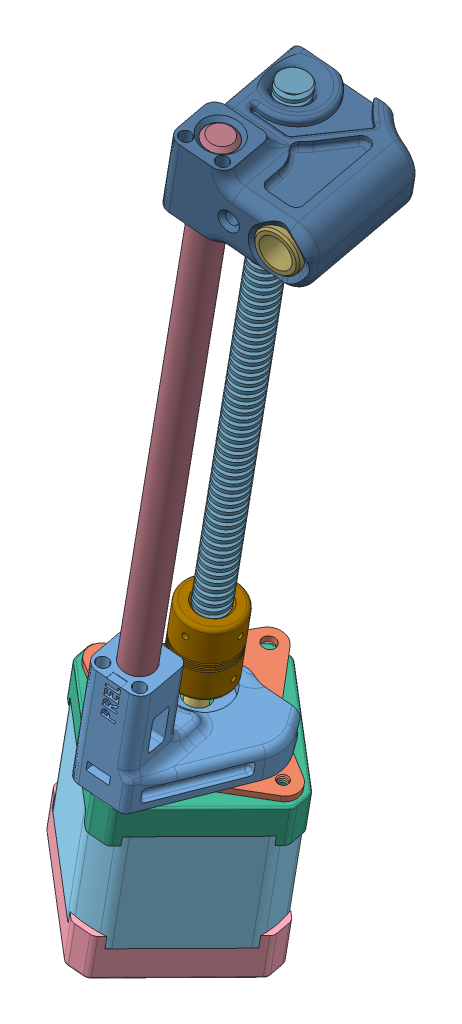
SolidWorks assembly PRUSA 3i elevator, configuration Default. Lengths in mm.
Overall size (115.58 237.83 82.21).
21 component instances, 14 part files, 7 mates.
Components (placement in the parent):
- lead motor assy-1: lead motor assy [Default] at (-145.707 134.5483 194.624) x (-0.101437 0.10188 -0.989612) z (0.968806 -0.21597 -0.121539) size (60.3 83.9 59.73)
  - x motor lead-1: x motor lead [Default] at (1.0016 21.1815 58.4436) size (38.44 32 28.56)
  - Nema 17 Damper v2-1: Nema 17 Damper v2 [Default] at (1.0013 -26.8185 65.4439) x (0.000014 0 -1) z (-1 0 -0.000014) size (52.04 7.74 51.84)
  - 17HM19-2004S-1: 17HM19-2004S [Default] at (-7.0367 -101.7185 75.8822) x (0.703083 0 -0.711108) z (0.711108 0 0.703083) size (42.24 72 42.24)
    - nema17_shaft_17HM19-2004S-1: nema17_shaft_17HM19-2004S [Default] at (13.0746 21 -1.623) x (-0.412738 0 0.91085) z (-0.91085 0 -0.412738) size (5 72 5)
    - nema17_bottom_17HM19-2004S-1: nema17_bottom_17HM19-2004S [Default] at (13.0746 21 -1.623) x (0.999984 0 0.005702) z (-0.005702 0 0.999984) size (42 12 42)
    - nema17_middle_17HM19-2004S-1: nema17_middle_17HM19-2004S [Default] at (13.0746 29.5 -1.623) x (0.999984 0 0.005702) z (-0.005702 0 0.999984) size (42 31.5 42)
    - nema17_top_17HM19-2004S-1: nema17_top_17HM19-2004S [Default] at (13.0746 61 -1.623) x (0.999984 0 0.005702) z (-0.005702 0 0.999984) size (42 12.6 42)
    - radial ball bearing_68_din_DIN 625 - 625 - 8,SI,NC,8_68-1: radial ball bearing_68_din_DIN 625 - 625 - 8,SI,NC,8_68 [Default] at (13.0746 26 -1.623) x (0 -1 0) z (0 0 1) size (5.01 16 16)
    - radial ball bearing_68_din_DIN 625 - 625 - 8,SI,NC,8_68-2: radial ball bearing_68_din_DIN 625 - 625 - 8,SI,NC,8_68 [Default] at (13.0746 67.1 -1.623) x (0 1 0) z (0 0 1) size (5.01 16 16)
    - countersunk flat head cross recess screw_din_ISO 7046-1 - M3 x 30 - Z --- 30N-1: countersunk flat head cross recess screw_din_ISO 7046-1 - M3 x 30 - Z --- 30N [Default] at (28.4859 21.6 13.9651) x (0 1 0) z (0.546944 0 -0.837169) size (30 5.5 5.5)
    - countersunk flat head cross recess screw_din_ISO 7046-1 - M3 x 30 - Z --- 30N-2: countersunk flat head cross recess screw_din_ISO 7046-1 - M3 x 30 - Z --- 30N [Default] at (28.6627 21.6 -17.0344) x (0 1 0) z (0.546944 0 -0.837169) size (30 5.5 5.5)
    - countersunk flat head cross recess screw_din_ISO 7046-1 - M3 x 30 - Z --- 30N-3: countersunk flat head cross recess screw_din_ISO 7046-1 - M3 x 30 - Z --- 30N [Default] at (-2.5136 21.6 13.7883) x (0 1 0) z (0.546944 0 -0.837169) size (30 5.5 5.5)
    - countersunk flat head cross recess screw_din_ISO 7046-1 - M3 x 30 - Z --- 30N-4: countersunk flat head cross recess screw_din_ISO 7046-1 - M3 x 30 - Z --- 30N [Default] at (-2.3368 21.6 -17.2112) x (0 1 0) z (0.546944 0 -0.837169) size (30 5.5 5.5)
  - 5-8 small-1: 5-8 small [Default] at (1.0016 -17.8185 65.4436) x (1 0 0) z (0 1 0) size (15.39 15.39 20)
- x lead idler block-1: x lead idler block [Default] at (21.2561 240.5118 190.8289) x (-0.101437 0.10188 -0.989612) z (-0.968806 0.21597 0.121539) size (40.45 19.18 38.53)
  - x idler lead mirror-1: x idler lead mirror [Default] at (3.3867 7.1769 80.8876) size (39.97 19.18 36.13)
  - instrument ball bearing_68_iso-1: instrument ball bearing_68_iso [ISO 1224 - 100822 - R,8,SI,NC,8_68] at (2.4627 4.6769 72.4222) x (0 -1 0) z (0 0 1) size (7 22 22)
  - brass sleeve 30mm-1: brass sleeve 30mm [Default] at (3.3867 0.1769 52.8876) x (0 0 1) z (-1 0 0) size (11 11 30)
- liscia da 8 400-1: liscia da 8 400 [Default] at (-31.2705 328.0362 224.5375) x (-0.870967 0.236844 -0.430491) z (-0.226108 -0.97107 -0.076794) size (8 8 167)
- LeadScrew 8mm x 2mmPitch 500-1: LeadScrew 8mm x 2mmPitch 500 [Default] at (-84.3777 112.0502 185.0093) x (-0.918359 0.186219 0.349198) z (-0.226108 -0.97107 -0.076794) size (9.24 8.22 159.1)
Mates (geometry in assembly coordinates):
- Coincidente1: coincident aligned: plane of lead motor assy-1/x motor lead-1 through (-84.3987 142.5969 188.1562) normal (-0.968806 0.21597 0.121539); plane of x lead idler block-1/x idler lead mirror-1 through (-59.0746 251.3568 196.7572) normal (-0.968806 0.21597 0.121539)
- Coincidente2: coincident aligned: plane of lead motor assy-1/x motor lead-1 through (-58.748 175.3598 219.2148) normal (0.101437 -0.10188 0.989612); plane of x lead idler block-1/x idler lead mirror-1 through (-53.7736 196.7233 220.9043) normal (0.101437 -0.10188 0.989612)
- Distanza1: distance = 130 mm anti-aligned: plane of lead motor assy-1/5-8 small-1 through (-81.9131 122.6348 185.8464) normal (0.226108 0.97107 0.076794); plane of x lead idler block-1/x idler lead mirror-1 through (-92.3388 256.4824 216.8625) normal (-0.226108 -0.97107 -0.076794)
- Concentrico2: concentric aligned: cylinder of lead motor assy-1/x motor lead-1 through (-83.2485 104.8054 206.8839) axis (0.226108 0.97107 0.076794) radius 4.05; cylinder of liscia da 8 400-1 through (-86.2589 91.8769 205.8615) axis (0.226108 0.97107 0.076794) radius 4
- Tangent3: tangent: cylinder of lead motor assy-1/5-8 small-1 through (-84.1742 112.9241 185.0784) axis (0.226108 0.97107 0.076794) radius 4; curve of LeadScrew 8mm x 2mmPitch 500-1
- Coincident2: coincident anti-aligned: plane of lead motor assy-1/17HM19-2004S-1/nema17_shaft_17HM19-2004S-1 through (-84.3777 112.0502 185.0093) normal (0.226108 0.97107 0.076794); plane of LeadScrew 8mm x 2mmPitch 500-1 through (-84.3777 112.0502 185.0093) normal (-0.226108 -0.97107 -0.076794)
- Coincident3: coincident aligned: cylinder of lead motor assy-1/5-8 small-1 through (-84.1742 112.9241 185.0784) axis (0.226108 0.97107 0.076794) radius 4; circle of LeadScrew 8mm x 2mmPitch 500-1
